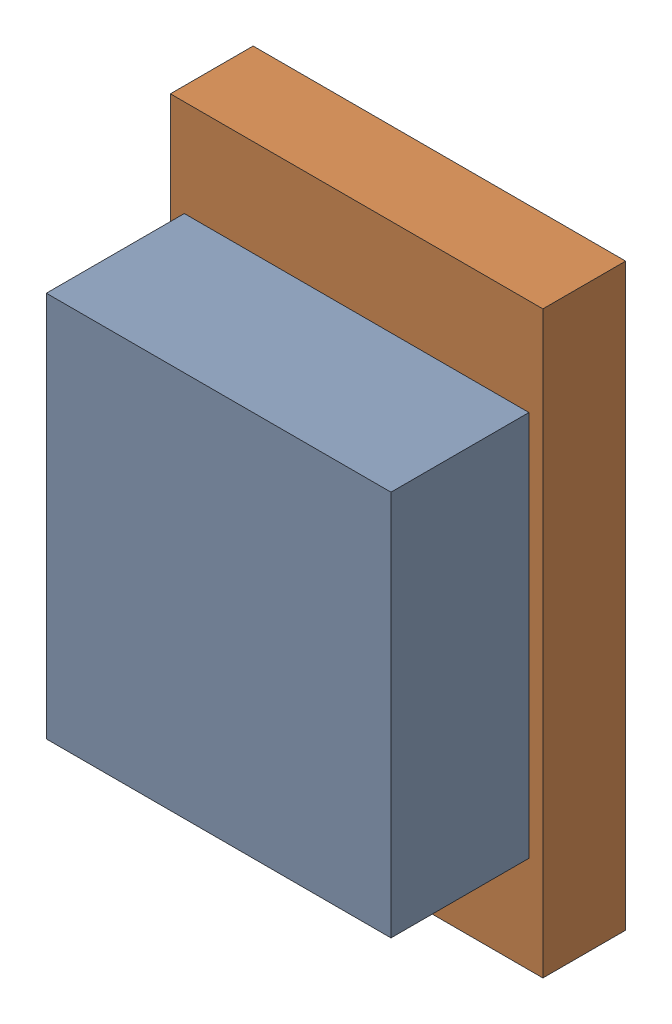
SolidWorks assembly D5, configuration Default. Lengths in mm.
Overall size (1.35 2.1 0.8).
4 component instances, 2 part files, 0 mates.
Components (placement in the parent):
- 6638399248-1: 6638399248 [Default] at (5.207 2.286 0.3) size (1.25 1.4 0.5)
  - Extruded_12-1: Extruded_12 [Default] at origin size (1.25 1.4 0.5)
- 6638399088-1: 6638399088 [Default] at (5.207 2.286 0) size (1.35 2.1 0.3)
  - Extruded_13-1: Extruded_13 [Default] at origin size (1.35 2.1 0.3)
